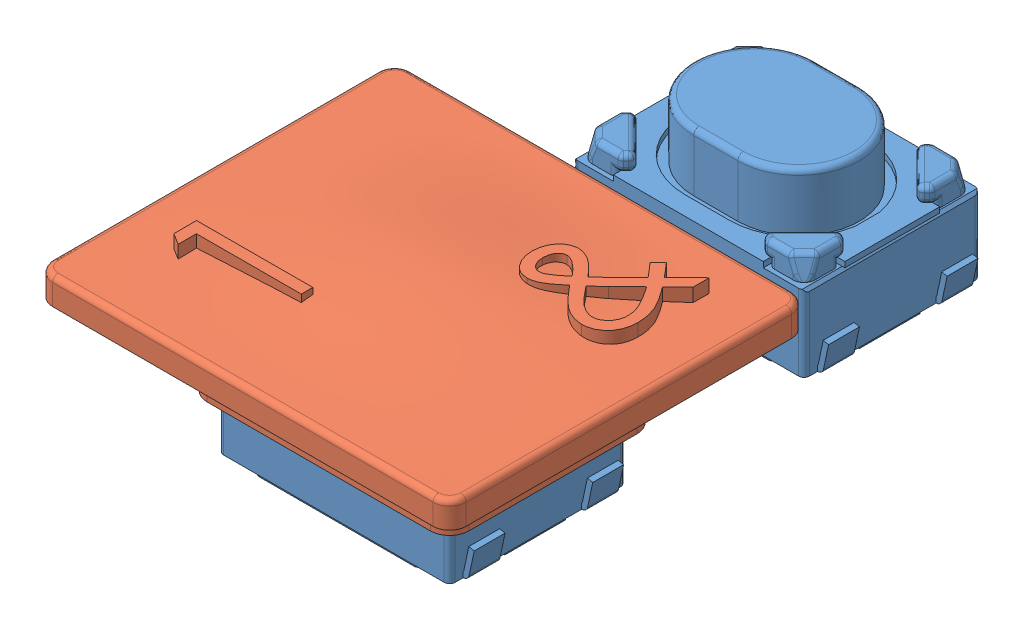
SolidWorks assembly keycapall, configuration Défaut. Lengths in mm.
Overall size (14.43 3.24 12.06).
3 component instances, 2 part files, 4 mates.
Components (placement in the parent):
- SKRPABE010-1: SKRPABE010 [Défaut] at (0.1589 -1.4694 4.5995) size (4.6 2.5 3.2)
- keycap-1: keycap [Défaut] at (0.1589 0.8587 4.5995) x (1 0 0) z (0 -1 0) size (14.43 7.26 2.21)
- SKRPABE010-2: SKRPABE010 [Défaut] at (0.1329 -1.4694 -1.8546) size (4.6 2.5 3.2)
Mates (geometry in assembly coordinates):
- Coïncidente1: coincident aligned: plane of SKRPABE010-1 through (0.1589 -1.4694 4.5995) normal (0 0 1); plane of keycap-1 through (0.1589 0.8587 4.5995) normal (0 0 1)
- Coïncidente2: coincident aligned: plane of SKRPABE010-1 through (0.1589 -1.4694 4.5995) normal (1 0 0); plane of keycap-1 through (0.1589 0.8587 4.5995) normal (1 0 0)
- Coïncidente3: coincident anti-aligned: plane of SKRPABE010-1 through (0.5589 1.0306 4.5995) normal (0 1 0); plane of keycap-1 through (0.5589 1.0308 4.5995) normal (0 -1 0)
- Coïncidente4: coincident aligned: plane of SKRPABE010-1 through (2.1589 -1.4694 3.0995) normal (0 -1 0); plane of SKRPABE010-2 through (2.1329 -1.4694 -3.3546) normal (0 -1 0)
